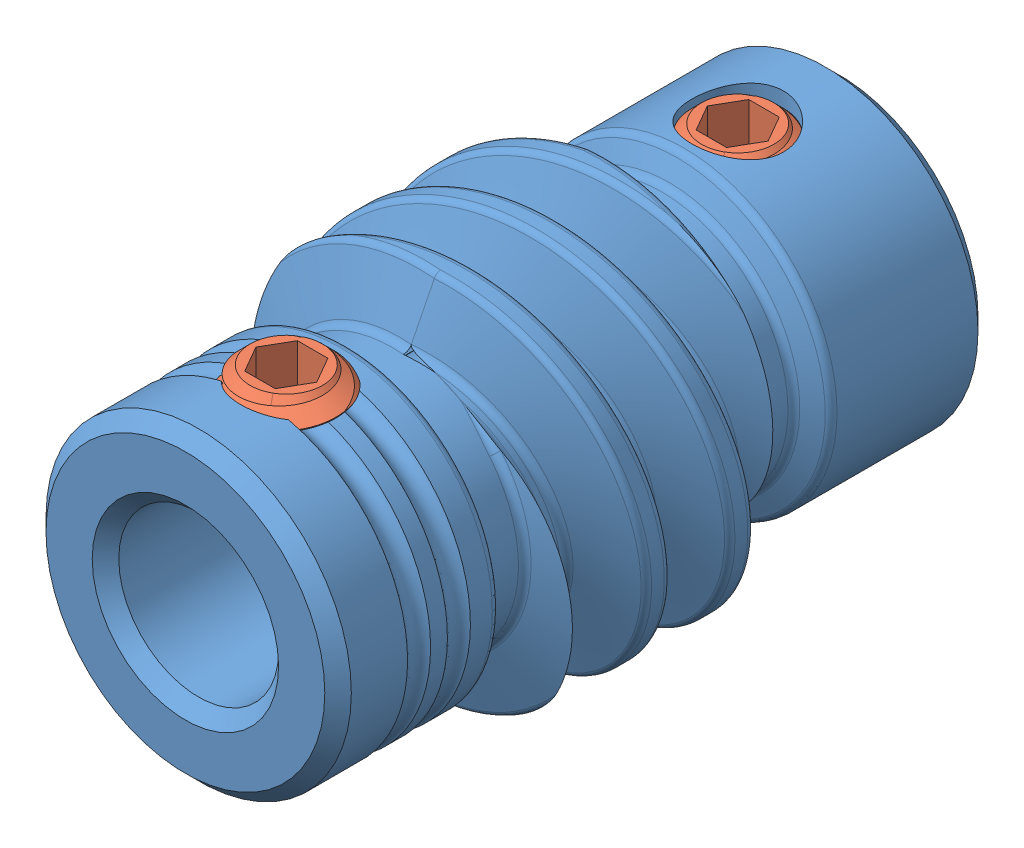
SolidWorks assembly Tetrix Worm Screw (10 to 1), configuration Default. Lengths in mm.
Overall size (14.86 15.12 24.6).
3 component instances, 2 part files, 0 mates.
Components (placement in the parent):
- Tetrix Worm Screw (10 to 1) Body-1: Tetrix Worm Screw (10 to 1) Body [Default] at origin size (14.86 15.12 24.6)
- Tetrix Worm Screw (10 to 1) Set Screw-1: Tetrix Worm Screw (10 to 1) Set Screw [Default] at (0 3.01 8.5) x (0.866025 0 -0.5) z (0.5 0 0.866025) size (4.08 3.31 3.99)
- Tetrix Worm Screw (10 to 1) Set Screw-2: Tetrix Worm Screw (10 to 1) Set Screw [Default] at (0 2.375 -8.5) x (0.866025 0 -0.5) z (0.5 0 0.866025) size (4.08 3.31 3.99)
